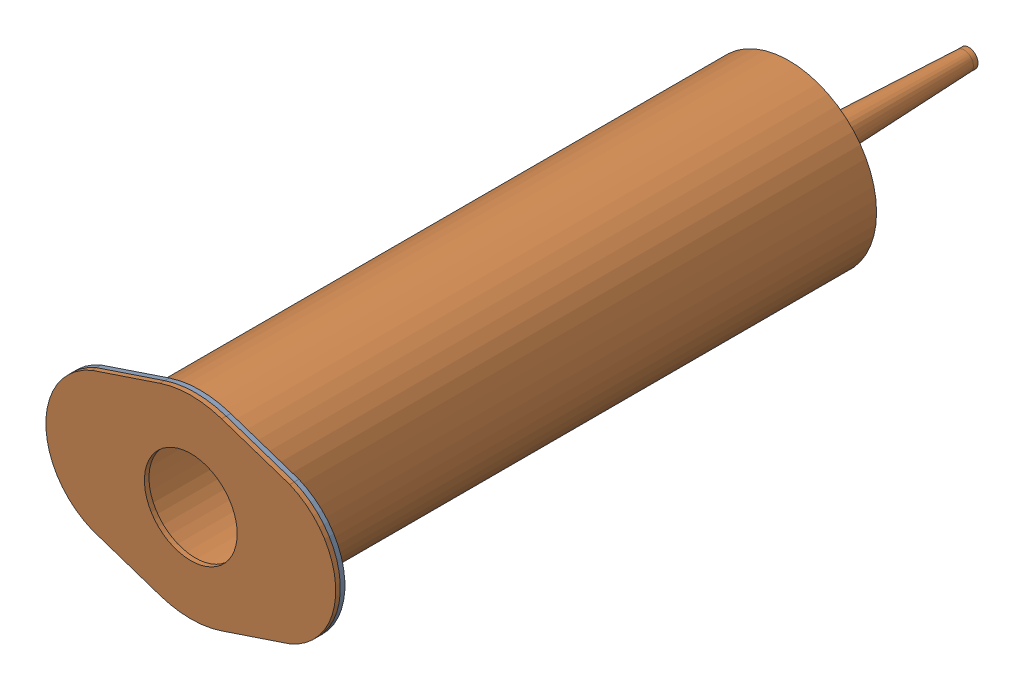
SolidWorks assembly syringe assembly, configuration Default. Lengths in mm.
Overall size (63 43.63 169.1).
2 component instances, 2 part files, 2 mates.
Components (placement in the parent):
- syringe outer-1: syringe outer [Default] at (-25.4932 25.576 -69.9236) size (63 42.1 169.1)
- syringe plunger-1: syringe plunger [Default] at (-25.4932 25.576 -57.7524) x (0.956098 0.293047 0) z (0.293047 -0.956098 0) size (34.92 50 34.92)
Mates (geometry in assembly coordinates):
- Concentric1: concentric aligned: cylinder of syringe outer-1 through (-25.4932 25.576 57.0764) axis (0 0 -1) radius 15.0812; cylinder of syringe plunger-1 through (-25.4932 25.576 -52.7524) axis (0 0 -1) radius 17.4625
- LimitDistance1: limit distance = 12.1711 mm anti-aligned: plane of syringe outer-1 through (-25.4932 25.576 -69.9236) normal (0 0 1); plane of syringe plunger-1 through (-25.4932 25.576 -57.7524) normal (0 0 -1)
